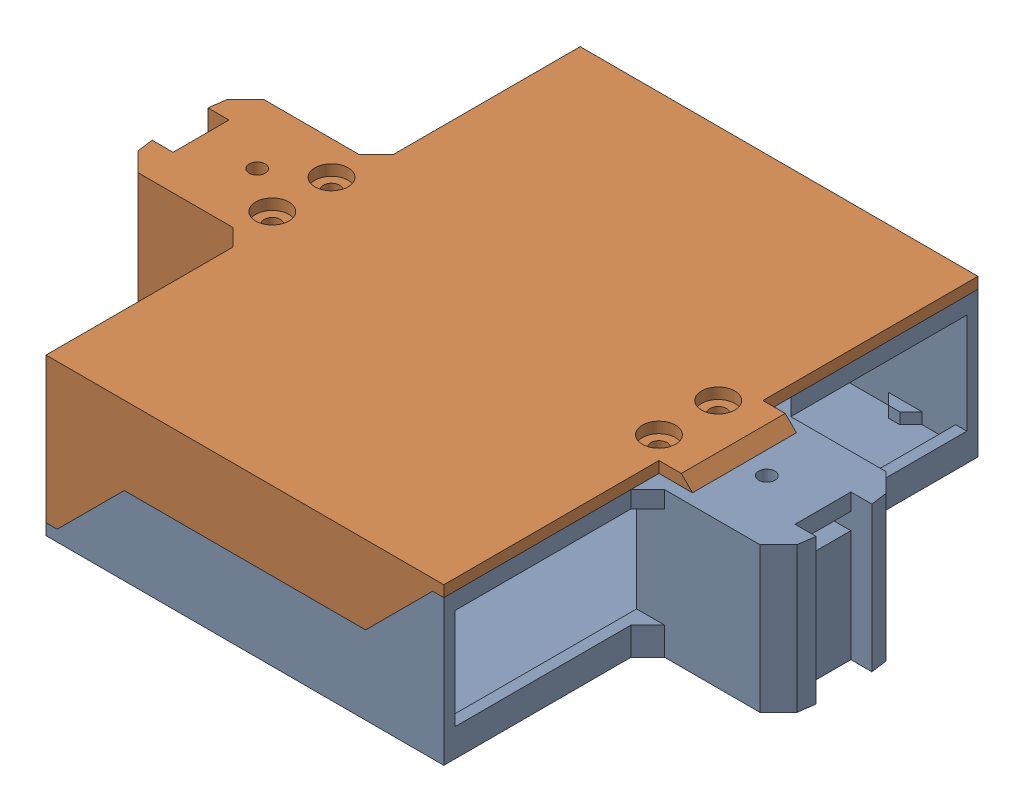
SolidWorks assembly Radio Module, configuration Default. Lengths in mm.
Overall size (150.9 35.56 121.41).
2 component instances, 1 part files, 9 mates.
Components (placement in the parent):
- Avionics Module Half Case-1: Avionics Module Half Case [Default] at origin size (138.44 33.02 121.41)
- Avionics Module Half Case-2: Avionics Module Half Case [Default] at (0 35.56 0) x (-1 0 0) z (0 0 1) size (138.44 33.02 121.41)
Mates (geometry in assembly coordinates):
- Coincident3: coincident anti-aligned: plane of Avionics Module Half Case-1 through (-27.4313 17.78 -60.706) normal (0 1 0); plane of Avionics Module Half Case-2 through (27.4313 17.78 -60.706) normal (0 -1 0)
- Coincident4: coincident aligned: plane of Avionics Module Half Case-1 through (-45.2113 2.54 60.706) normal (0 0 1); plane of Avionics Module Half Case-2 through (45.2113 33.02 60.706) normal (0 0 1)
- Coincident5: coincident aligned: plane of Avionics Module Half Case-1 through (45.2113 2.54 60.706) normal (1 0 0); plane of Avionics Module Half Case-2 through (45.2113 33.02 60.706) normal (1 0 0)
- Coincident6: coincident: plane of Avionics Module Half Case-1 through (0 5.08 0) normal (0 1 0); plane of Radio PCB.step-2/16-soldermask.step-1 through (4.5713 5.08 0) normal (0 -1 0)
- Coincident7: coincident: plane of Avionics Module Half Case-1 through (52.8313 -23.1743 11.811) normal (-1 0 0); plane of Radio PCB.step-2/Board.step-1 through (52.8313 5.1325 11.43) normal (1 0 0)
- Width1: width anti-aligned: plane of Avionics Module Half Case-1 through (-45.2113 33.02 58.166) normal (0 0 -1); plane of Avionics Module Half Case-1 through (-45.2113 33.02 -58.166) normal (0 0 1); plane of Radio PCB.step-2/Board.step-1 through (-41.1487 5.1325 57.15) normal (0 0 1); plane of Radio PCB.step-2/Board.step-1 through (42.6713 5.1325 -57.15) normal (0 0 -1)
- Coincident8: coincident: plane of Avionics Module Half Case-1 through (0 5.08 0) normal (0 1 0); plane of Radio PCB.step-3/16-soldermask_3.step-1 through (4.5713 5.08 -59.1989) normal (0 -1 0)
- Coincident9: coincident: plane of Avionics Module Half Case-1 through (42.6713 33.02 -58.166) normal (-1 0 0); plane of Radio PCB.step-3/Board_3.step-1 through (42.6713 5.1325 -70.6289) normal (1 0 0)
- Width3: width aligned: plane of Avionics Module Half Case-1 through (-45.2113 33.02 58.166) normal (0 0 -1); plane of Radio PCB.step-3/Board_3.step-1 through (-45.2113 33.02 -58.166) normal (0 0 1); plane of Avionics Module Half Case-1 through (42.6713 5.1325 -57.15) normal (0 0 -1); plane of Radio PCB.step-3/Board_3.step-1 through (-41.1487 5.1325 57.15) normal (0 0 1)
